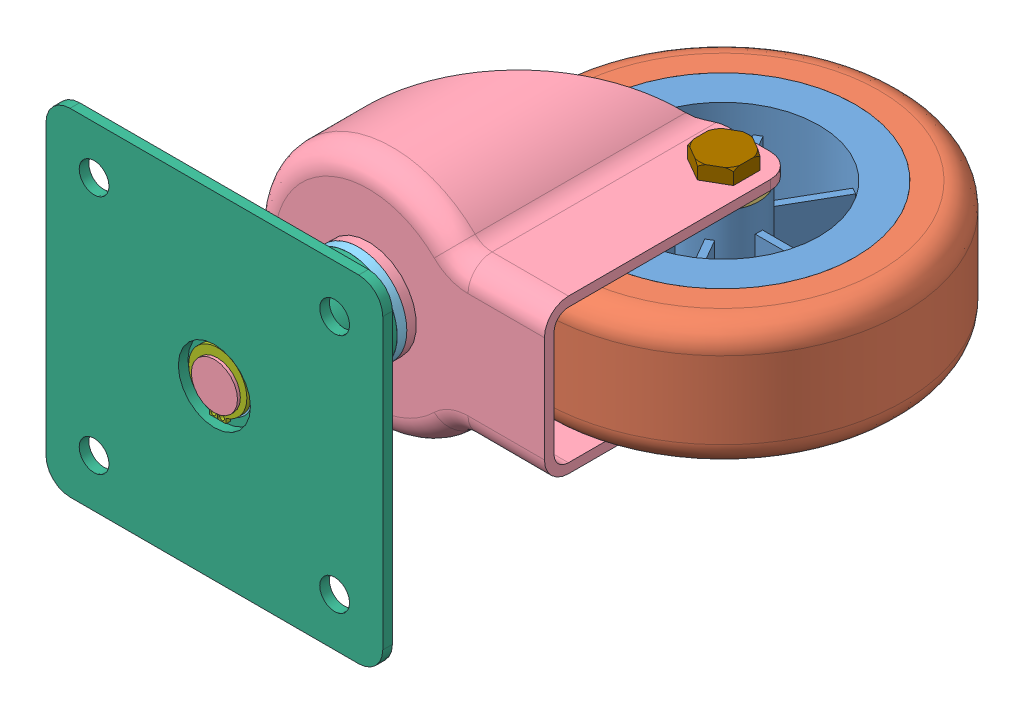
SolidWorks assembly Assem2, configuration Default. Lengths in mm.
Overall size (101.4 70 114.3).
11 component instances, 10 part files, 22 mates.
Components (placement in the parent):
- wheel-1: wheel [Default] at origin size (55 26.04 55)
- tire-3: tire [Default] at (0 13 0) size (75 26 75)
- Washer-4: Washer [Default] at (-0.0006 25.9444 0) x (0.999924 0.012354 0) z (0 0 1) size (15 1 15)
- Washer-5: Washer [Default] at (-0.0006 0.0556 0) x (0.999924 -0.012354 0) z (0 0 -1) size (15 1 15)
- wheel carrier-1: wheel carrier [Default] at (-28.9 13 57.6974) x (1 0 0) z (0 -1 0) size (61.1 84 49)
- bearing -1: bearing  [Default] at (-28.9 13 57.6544) x (0 1 0) z (1 0 0) size (20 28 20)
- Support plate -2: Support plate  [Default] at (-28.9 13 74.8) x (1 0 0) z (0 -1 0) size (70 28 70)
- Ring-2: Ring [Default] at (-28.9 13.5 75.1) x (1 0 0) z (0 -1 0) size (12.09 1 12.84)
- pipe-1: pipe [Default] at (0.3799 30.8549 0) x (0.999924 -0.012354 0) z (0 0 1) size (9 26 9)
- screw M6-1: screw M6 [Default] at (0.2 -9 0.0106) size (9.53 41 11)
- screw nut m6-1: screw nut m6 [Default] at (0.2 -8 0) size (9.53 5.33 11)
Mates (geometry in assembly coordinates):
- Coincident2: coincident: plane of wheel-1 through (-24.9 1 0) normal (0 1 0); plane of tire-3 through (0 1 0) normal (0 -1 0)
- Coincident3: coincident: plane of tire-3 through (0 13 0) normal (1 0 0); plane of assembly through (0 0 0) normal (1 0 0)
- Coincident4: coincident: plane of tire-3 through (0 13 0) normal (0 0 1); plane of assembly through (0 0 0) normal (0 0 1)
- Tangent7: tangent: cone of wheel-1 through (0 26 0) axis (0 -1 0); plane of Washer-4 through (-0.0006 25.9444 0) normal (0.012354 -0.999924 0)
- Coincident10: coincident: plane of Washer-4 through (-0.0006 25.9444 0) normal (0 0 1); plane of assembly through (0 0 0) normal (0 0 1)
- Coincident11: coincident: plane of tire-3 through (0 13 0) normal (0 1 0); plane of wheel carrier-1 through (-28.9 13 57.6974) normal (0 -1 0)
- Distance1: distance = 7.7 mm: plane of assembly through (0 0 0) normal (1 0 0); plane of wheel carrier-1 through (7.7 -3 -7.2) normal (1 0 0)
- Distance3: distance = 7.2 mm: plane of wheel carrier-1 through (-28.9 13 -7.2) normal (0 0 -1); plane of pipe-1 through (0.3799 30.8549 0) normal (0 0 1)
- Coincident14: coincident: plane of wheel carrier-1 through (-33.9 13 46.8) normal (0 0 1); plane of bearing -1 through (-28.9 8 46.8) normal (0 0 -1)
- Coincident15: coincident: circle of wheel carrier-1; circle of bearing -1
- Coincident26: coincident: plane of bearing -1 through (-28.9 3 48.8) normal (0 0 1); plane of Support plate -2 through (-28.9 13 48.8) normal (0 0 -1)
- Coincident27: coincident: plane of wheel carrier-1 through (-28.9 13 57.6974) normal (1 0 0); plane of Support plate -2 through (-28.9 13 74.8) normal (1 0 0)
- Coincident28: coincident: plane of wheel carrier-1 through (-28.9 13 57.6974) normal (0 -1 0); plane of Support plate -2 through (-28.9 13 74.8) normal (0 -1 0)
- Coincident29: coincident: plane of wheel carrier-1 through (-28.9 13 57.6974) normal (1 0 0); plane of Ring-2 through (-28.9 13.5 75.1) normal (1 0 0)
- Concentric6: concentric: cylinder of wheel carrier-1 through (-28.9 13 46.8) axis (0 0 1) radius 4.4; cylinder of Ring-2 through (-28.9 13 76.1) axis (0 0 -1) radius 4.4
- Coincident30: coincident: plane of wheel carrier-1 through (-33.9 13 75.1) normal (0 0 1); plane of Ring-2 through (-28.9 13.5 75.1) normal (0 0 -1)
- Coincident31: coincident: circle of Washer-5; circle of pipe-1
- Concentric7: concentric: circle of wheel carrier-1; circle of screw M6-1
- Coincident33: coincident: plane of wheel carrier-1 through (7.7 29 -7.2) normal (0 1 0); plane of screw M6-1 through (-2.8 29 0.0106) normal (0 -1 0)
- Coincident34: coincident: plane of wheel carrier-1 through (7.7 -3 -7.2) normal (0 -1 0); plane of screw nut m6-1 through (0.2 -3 0) normal (0 1 0)
- Coincident35: coincident: plane of screw M6-1 through (0.2 -9 0.0106) normal (1 0 0); plane of screw nut m6-1 through (0.2 -8 0) normal (1 0 0)
- Coincident36: coincident: plane of pipe-1 through (0.3799 30.8549 0) normal (0 0 1); plane of screw nut m6-1 through (0.2 -8 0) normal (0 0 1)
